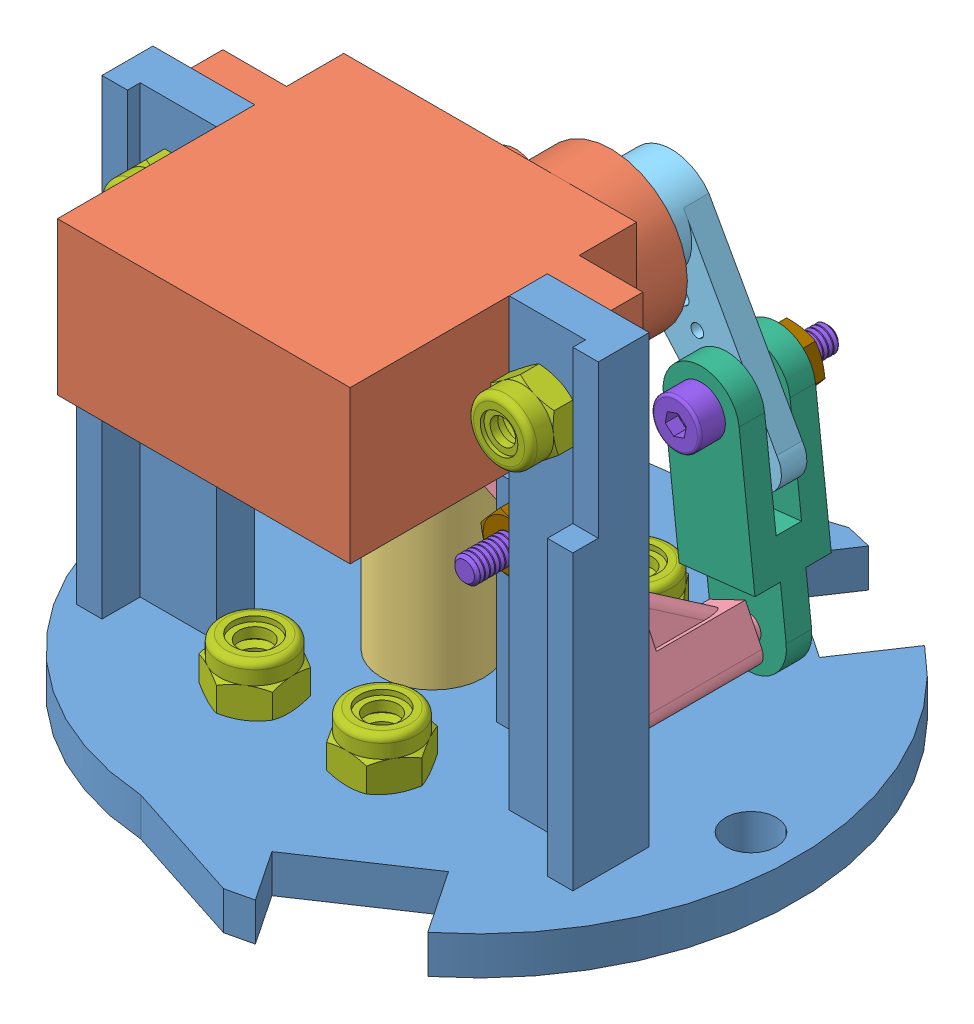
SolidWorks assembly Rückseite, configuration Standard. Lengths in mm.
Overall size (50 42.97 49.14).
19 component instances, 10 part files, 39 mates.
Components (placement in the parent):
- Backside-1: Backside [Standard] at (-0.7502 -6.4244 50) size (50 38 49.14)
- servo-1: servo [Standard] at (-9.7502 31.5756 70.5) x (1 0 0) z (0 1 0) size (33 29.25 12)
- Drücker-1: Drücker [Standard] at (1.0875 17.6023 21.7522) x (-1 0 0) z (0 0 1) size (8 29 8)
- Hebel-1: Hebel [Standard] at (9.2498 10.5756 49) x (0.911012 -0.412381 0) z (0 0 1) size (29.78 9.71 13)
- Servo-Arm-1: Servo-Arm [Standard] at (7.2498 25.5756 39.25) x (0.576199 -0.817309 0) z (-0.817309 -0.576199 0) size (20.6 4.3 7.2)
- Hebel2-1: Hebel2 [Standard] at (15.2837 1.6814 39.25) x (-0.113044 0.99359 0) z (0.99359 0.113044 0) size (21 6 6)
- User Library-Mutter DIN-985_-1: User Library-Mutter DIN-985_ [Mutter DIN-985 M3-A2] at (-4.7502 -3.4244 60) x (0 1 0) z (-0.455135 0 0.890422) size (4 6.35 5.5)
- User Library-Mutter DIN-985_-2: User Library-Mutter DIN-985_ [Mutter DIN-985 M3-A2] at (5.2498 -3.4244 60) x (0 1 0) z (-0.871788 0 0.489884) size (4 6.35 5.5)
- User Library-Mutter DIN-985_-3: User Library-Mutter DIN-985_ [Mutter DIN-985 M3-A2] at (5.2498 -3.4244 40) x (0 1 0) z (-0.77566 0 0.631152) size (4 6.35 5.5)
- User Library-Mutter DIN-985_-4: User Library-Mutter DIN-985_ [Mutter DIN-985 M3-A2] at (-4.7502 -3.4244 40) x (0 1 0) z (-0.229708 0 0.97326) size (4 6.35 5.5)
- socket head cap screw 4762_din-1: socket head cap screw 4762_din [ISO 4762 M2 x 10 --- 10S] at (9.2498 10.5756 45.5) x (0 0 1) z (0 -1 0) size (12 3.8 3.8)
- socket head cap screw 4762_din-2: socket head cap screw 4762_din [ISO 4762 M2 x 10 --- 10S] at (-0.7502 15.1023 45) x (0 0 1) z (0.522585 0.852587 0) size (12 3.8 3.8)
- socket head cap screw 4762_din-3: socket head cap screw 4762_din [ISO 4762 M2 x 10 --- 10S] at (13.588 16.5852 45.25) x (0 0 -1) z (-0.325588 0.945512 0) size (12 3.8 3.8)
- nut__style_1__m2x0_4__ansi_b18_2_4_1m-1: nut__style_1__m2x0_4__ansi_b18_2_4_1m [Default] at (-0.7502 15.1023 53) x (0.980747 -0.195284 0) z (0 0 1) size (4.62 4 1.6)
- nut__style_1__m2x0_4__ansi_b18_2_4_1m-2: nut__style_1__m2x0_4__ansi_b18_2_4_1m [Default] at (13.588 16.5852 35.65) x (0.980747 -0.195284 0) z (0 0 1) size (4.62 4 1.6)
- nut__style_1__m2x0_4__ansi_b18_2_4_1m-3: nut__style_1__m2x0_4__ansi_b18_2_4_1m [Default] at (9.2498 10.5756 52.5) x (0.980747 -0.195284 0) z (0 0 1) size (4.62 4 1.6)
- User Library-Mutter DIN-985_-5: User Library-Mutter DIN-985_ [Mutter DIN-985 M2,5-A2] at (-12.7502 25.5756 58) x (0 0 1) z (0.965495 0.260421 0) size (3.8 5.77 5)
- User Library-Mutter DIN-985_-6: User Library-Mutter DIN-985_ [Mutter DIN-985 M2,5-A2] at (16.2498 25.5756 58) x (0 0 1) z (-0.395566 -0.918438 0) size (3.8 5.77 5)
- oval head sheet metal screw_din-1: oval head sheet metal screw_din [Tapping screw DIN 7983-ST2.9x6.5-F-H-S] at (7.2498 25.5756 40.6565) x (0 0 1) z (-0.615967 -0.787772 0) size (7.15 5.82 5.82)
Mates (geometry in assembly coordinates):
- Konzentrisch1: concentric anti-aligned: cylinder of Drücker-1 through (-0.7502 -27.687 50) axis (0 1 0) radius 4; cylinder of Backside-1 through (-0.7502 -3.4244 50) axis (0 -1 0) radius 4
- Konzentrisch2: concentric anti-aligned: cylinder of Backside-1 through (9.2498 10.5756 42.5) axis (0 0 1) radius 1; cylinder of Hebel-1 through (9.2498 10.5756 51) axis (0 0 -1) radius 1
- Deckungsgleich1: coincident anti-aligned: plane of Backside-1 through (6.7498 13.5756 51) normal (0 0 -1); plane of Hebel-1 through (9.2498 10.5756 51) normal (0 0 1)
- Parallel1: parallel anti-aligned: plane of Drücker-1 through (4.2498 -6.687 49) normal (0 0 1); plane of Hebel-1 through (9.2498 10.5756 49) normal (0 0 -1)
- Tangential1: tangent anti-aligned: cylinder of Drücker-1 through (-0.7502 -1.187 46) axis (0 0 1) radius 1; plane of Hebel-1 through (10.0117 9.9279 51) normal (-0.761884 0.647714 0)
- Konzentrisch3: concentric anti-aligned: cylinder of servo-1 through (7.2498 25.5756 44) axis (0 0 1) radius 6; cylinder of Servo-Arm-1 through (7.2498 25.5756 43.55) axis (0 0 -1) radius 2.25
- Deckungsgleich6: coincident anti-aligned: plane of Backside-1 through (-9.7502 31.5756 58) normal (1 0 0); plane of servo-1 through (-9.7502 31.5756 48) normal (-1 0 0)
- Deckungsgleich7: coincident anti-aligned: plane of Backside-1 through (-9.7502 31.5756 55) normal (0 0 -1); plane of servo-1 through (18.2498 31.5756 55) normal (0 0 1)
- Deckungsgleich11: coincident aligned: plane of Backside-1 through (-0.7502 31.5756 50) normal (0 1 0); plane of servo-1 through (-9.7502 31.5756 48) normal (0 1 0)
- Deckungsgleich9: coincident anti-aligned: plane of Servo-Arm-1 through (7.2498 25.5756 39.25) normal (0 0 -1); plane of Hebel2-1 through (19.4636 13.9215 39.25) normal (0 0 1)
- Konzentrisch4: concentric anti-aligned: cylinder of Hebel-1 through (19.4636 13.9215 38) axis (0 0 1) radius 1; cylinder of Hebel2-1 through (19.4636 13.9215 41.25) axis (0 0 -1) radius 1
- Deckungsgleich12: coincident anti-aligned: plane of servo-1 through (7.2498 25.5756 41.25) normal (0 0 -1); plane of Servo-Arm-1 through (7.2498 25.5756 41.25) normal (0 0 1)
- Konzentrisch5: concentric aligned: cylinder of Servo-Arm-1 through (17.7591 28.8243 41.25) axis (0 0 -1) radius 0.5; cylinder of Hebel2-1 through (17.7591 28.8243 41.25) axis (0 0 -1) radius 1
- Deckungsgleich28: coincident anti-aligned: plane of Backside-1 through (-0.7502 -3.4244 50) normal (0 1 0); plane of User Library-Mutter DIN-985_-1 through (-7.1799 -3.4244 58.7581) normal (0 -1 0)
- Deckungsgleich29: coincident anti-aligned: plane of Backside-1 through (-0.7502 -3.4244 50) normal (0 1 0); plane of User Library-Mutter DIN-985_-2 through (3.9131 -3.4244 57.6211) normal (0 -1 0)
- Deckungsgleich31: coincident anti-aligned: plane of Backside-1 through (-0.7502 -3.4244 50) normal (0 1 0); plane of User Library-Mutter DIN-985_-3 through (3.5276 -3.4244 37.8834) normal (0 -1 0)
- Deckungsgleich30: coincident anti-aligned: plane of Backside-1 through (-0.7502 -3.4244 50) normal (0 1 0); plane of User Library-Mutter DIN-985_-4 through (-7.4059 -3.4244 39.3732) normal (0 -1 0)
- Deckungsgleich21: coincident anti-aligned: plane of Backside-1 through (6.7498 13.5756 47.5) normal (0 0 -1); plane of socket head cap screw 4762_din-1 through (7.3498 10.5756 47.5) normal (0 0 1)
- Konzentrisch20: concentric anti-aligned: cylinder of Backside-1 through (9.2498 10.5756 42.5) axis (0 0 1) radius 1; cylinder of socket head cap screw 4762_din-1 through (9.2498 10.5756 13.75) axis (0 0 -1) radius 1
- Konzentrisch19: concentric anti-aligned: cylinder of Drücker-1 through (-0.7502 -1.187 46) axis (0 0 1) radius 1; cylinder of socket head cap screw 4762_din-2 through (-0.7502 -1.187 13.25) axis (0 0 -1) radius 1
- Deckungsgleich38: coincident anti-aligned: plane of Hebel2-1 through (19.4636 13.9215 43.25) normal (0 0 1); plane of socket head cap screw 4762_din-3 through (15.9627 28.2057 43.25) normal (0 0 -1)
- Konzentrisch38: concentric anti-aligned: cylinder of Hebel2-1 through (17.7591 28.8243 41.25) axis (0 0 -1) radius 1; cylinder of socket head cap screw 4762_din-3 through (17.7591 28.8243 77) axis (0 0 1) radius 1
- Deckungsgleich41: coincident anti-aligned: plane of Drücker-1 through (-5.7502 -6.687 53) normal (0 0 1); plane of nut__style_1__m2x0_4__ansi_b18_2_4_1m-1 through (1.5153 -1.6381 53) normal (0 0 -1)
- Konzentrisch49: concentric aligned: circle of socket head cap screw 4762_din-2; circle of nut__style_1__m2x0_4__ansi_b18_2_4_1m-1
- Deckungsgleich39: coincident anti-aligned: plane of Hebel2-1 through (19.4636 13.9215 37.25) normal (0 0 -1); plane of nut__style_1__m2x0_4__ansi_b18_2_4_1m-2 through (20.0247 28.3732 37.25) normal (0 0 1)
- Konzentrisch50: concentric anti-aligned: circle of socket head cap screw 4762_din-3; circle of nut__style_1__m2x0_4__ansi_b18_2_4_1m-2
- Deckungsgleich33: coincident anti-aligned: plane of Backside-1 through (6.7498 13.5756 52.5) normal (0 0 1); plane of nut__style_1__m2x0_4__ansi_b18_2_4_1m-3 through (11.5153 10.1245 52.5) normal (0 0 -1)
- Konzentrisch48: concentric aligned: circle of socket head cap screw 4762_din-1; circle of nut__style_1__m2x0_4__ansi_b18_2_4_1m-3
- Deckungsgleich36: coincident anti-aligned: plane of Backside-1 through (-9.7502 31.5756 58) normal (0 0 1); plane of User Library-Mutter DIN-985_-5 through (-12.1447 23.3307 58) normal (0 0 -1)
- Deckungsgleich37: coincident anti-aligned: plane of Backside-1 through (13.2498 31.5756 58) normal (0 0 1); plane of User Library-Mutter DIN-985_-6 through (14.1143 26.4954 58) normal (0 0 -1)
- Konzentrisch51: concentric aligned: circle of Backside-1; circle of User Library-Mutter DIN-985_-1
- Konzentrisch52: concentric aligned: circle of Backside-1; circle of User Library-Mutter DIN-985_-2
- Konzentrisch53: concentric aligned: circle of Backside-1; circle of User Library-Mutter DIN-985_-4
- Konzentrisch54: concentric aligned: circle of Backside-1; circle of User Library-Mutter DIN-985_-3
- Konzentrisch55: concentric anti-aligned: circle of Backside-1; circle of User Library-Mutter DIN-985_-5
- Konzentrisch56: concentric anti-aligned: circle of Backside-1; circle of User Library-Mutter DIN-985_-6
- Deckungsgleich40: coincident anti-aligned: plane of Drücker-1 through (-5.7502 -6.687 47) normal (0 0 -1); plane of socket head cap screw 4762_din-2 through (0.8697 -2.1799 47) normal (0 0 1)
- Konzentrisch58: concentric anti-aligned: circle of Servo-Arm-1; circle of oval head sheet metal screw_din-1
- Tangential8: tangent: plane of Servo-Arm-1 through (7.2498 25.5756 39.25) normal (0 0 -1); circle of oval head sheet metal screw_din-1
